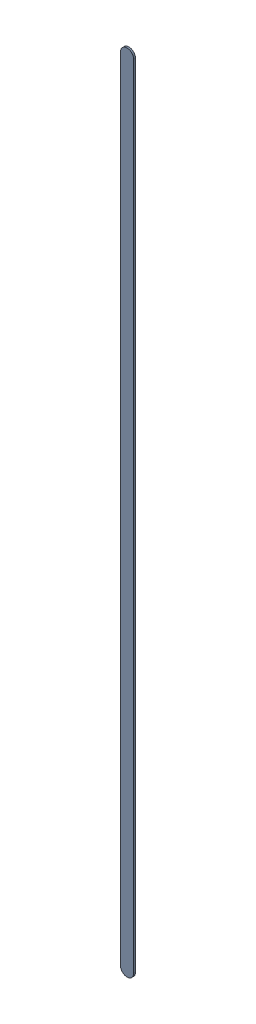
SolidWorks assembly Track (10.2mm,37.8mm)(10.2mm,53.1mm) on Top Layer, configuration Predeterminado. Lengths in mm.
Overall size (0.25 15.55 0.04).
2 component instances, 1 part files, 0 mates.
Components (placement in the parent):
- Track (10.2mm,37.8mm)(10.2mm,53.1mm) on Top Layer-1-1: Track (10.2mm,37.8mm)(10.2mm,53.1mm) on Top Layer-1 [Predeterminado] at (-68.317 -44.187 -0.0457) size (0.25 15.55 0.04)
  - Track (10.2mm,37.8mm)(10.2mm,53.1mm) on Top Layer-Part-1-1: Track (10.2mm,37.8mm)(10.2mm,53.1mm) on Top Layer-Part-1 [Predeterminado] at origin size (0.25 15.55 0.04)
